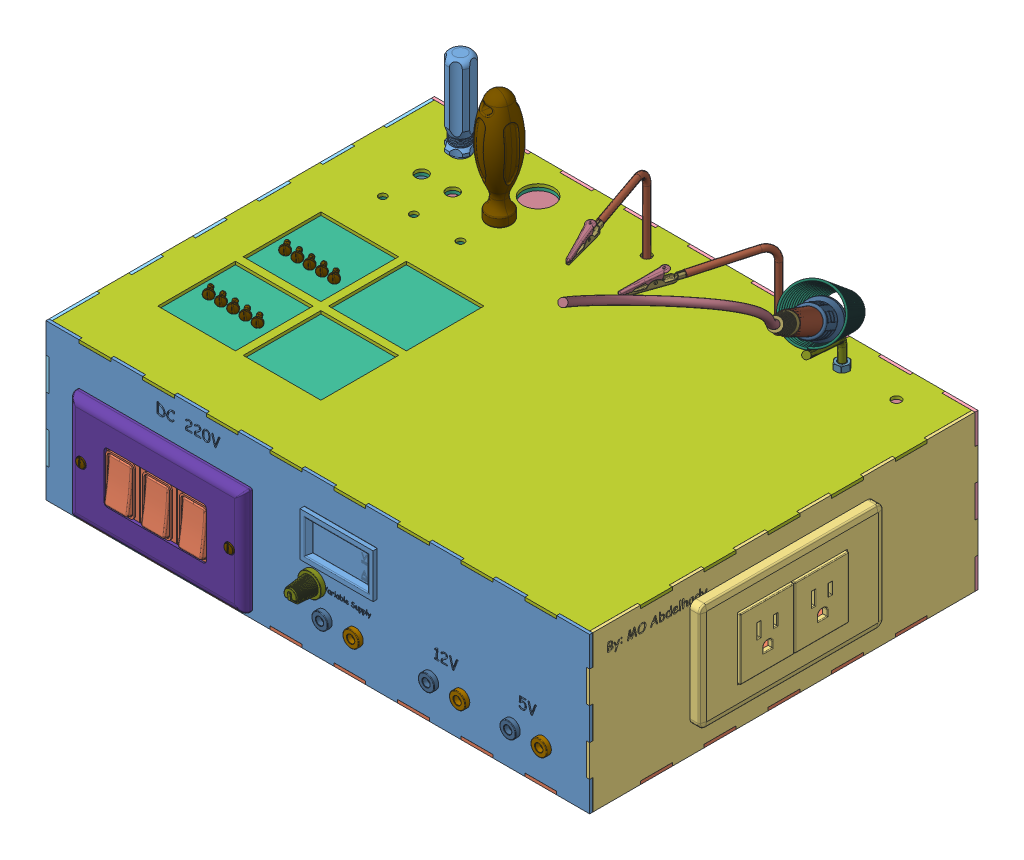
SolidWorks assembly Assem1, configuration Default. Lengths in mm.
Overall size (494.19 440.25 387.65).
70 component instances, 40 part files, 94 mates.
Components (placement in the parent):
- Part1-2: Part1 [Default] at (-4708.236 -838.5854 8887.5) size (355.6 101.6 2)
- Part5-2: Part5 [Default] at (-4427.6361 358.0877 11910.8107) x (1 0 0) z (0 1 0) size (355.6 254 2)
- Part2-1: Part2 [Default] at (116.9116 1704.849 11965.8396) x (0 -1 0) z (1 0 0) size (101.6 254 2)
- Part3-1: Part3 [Default] at (-4417.07 -837.1123 8635.4656) size (355.6 101.6 2)
- Part4-1: Part4 [Default] at (-186.7202 1702.8877 5671.7962) x (0 -1 0) z (-1 0 0) size (101.6 254 2)
- Part7-1: Part7 [Default] at (-1787.3775 455.6877 11453.9433) x (1 0 0) z (0 1 0) size (132.08 218.44 2)
- Part6-2: Part6 [Default] at (-4806.0896 457.6877 12028.9804) x (1 0 0) z (0 1 0) size (355.6 254 2)
- pot-1: pot [Default] at (-37.3978 423.1359 8904.7656) x (0 0 1) z (-1 0 0) size (29.51 24 17)
- banana_red-1: banana_red [Female, Banana Plug] at (-10.4767 405.8848 8916.4654) x (-0.682339 -0.731036 0) z (0 0 -1) size (10.54 10.54 28.12)
- banana_red-2: banana_red [Female, Banana Plug] at (59.2002 405.8848 8916.4654) x (0.821462 0.570264 0) z (0 0 -1) size (10.54 10.54 28.12)
- banana_red-3: banana_red [Female, Banana Plug] at (112.5315 405.8176 8916.4654) x (0.982462 0.186463 0) z (0 0 -1) size (10.54 10.54 28.12)
- banana_black-1: banana_black [Female, Banana Plug] at (-30.7967 405.8848 8916.4654) x (-0.579177 0.815202 0) z (0 0 -1) size (10.54 10.54 28.12)
- banana_black-2: banana_black [Female, Banana Plug] at (38.8802 405.8848 8916.4654) x (0.358694 0.933455 0) z (0 0 -1) size (10.54 10.54 28.12)
- banana_black-3: banana_black [Female, Banana Plug] at (92.2115 405.8176 8916.4654) x (-0.984112 -0.177551 0) z (0 0 -1) size (10.54 10.54 28.12)
- gang-1: gang [Default] at (-119.8752 393.7363 8922.0156)
- ss-2: ss [Default] at (-179.636 431.6464 8913.5932)
- ss-3: ss [Default] at (162.4549 435.7717 8943.6286)
- ss-4: ss [Default] at (-211.6466 368.7355 8918.2875)
- Part28-1: Part28 [Default] at (33.1958 473.157 8680.0698) x (-0.265256 0 0.964178) z (-0.964178 0 -0.265256) size (52 152 4)
- Part28-2: Part28 [Default] at (-53.1642 473.157 8680.0698) x (0.327401 0 0.944885) z (-0.944885 0 0.327401) size (52 152 4)
- Crocodile Clip.STEP-1: Crocodile Clip.STEP [Default] at (-30.6867 532.0877 8743.7186) x (0.944885 0 -0.327401) z (0.327401 0 0.944885) size (5.6 9.22 35.15)
  - Crocodile clip_01.STEP-1: Crocodile clip_01.STEP [Default] x (-1 0 0) z (0 0 -1) size (5.6 6.69 35)
  - Crocodile clip_02.STEP-1: Crocodile clip_02.STEP [Default] at (0 -0.0209 0) x (-1 0 0) z (0 0 -1) size (5.6 9.22 27.41)
- Crocodile Clip.STEP-2: Crocodile Clip.STEP [Default] at (14.9054 532.0877 8745.0457) x (0.964178 0 0.265256) z (-0.265256 0 0.964178) size (5.6 9.22 35.15)
  - Crocodile clip_01.STEP-1: Crocodile clip_01.STEP [Default] x (-1 0 0) z (0 0 -1) size (5.6 6.69 35)
  - Crocodile clip_02.STEP-1: Crocodile clip_02.STEP [Default] at (0 -0.0209 0) x (-1 0 0) z (0 0 -1) size (5.6 9.22 27.41)
- Switch KCD2 16A 220V-1: Switch KCD2 16A 220V [默认] at (102.178 430.6557 8657.4656) x (1 0 0) z (0 0 -1) size (25.5 32.5 34.2)
- plug v2.step-1: plug v2.step [Default] at (-68.1079 343.9302 8680.6226) x (0.174516 0.48804 0.855197) z (0.287949 0.805262 -0.518303) size (51.69 23.18 116.16)
  - socket.step-1: socket.step [Default] at origin size (51.69 23.18 116.16)
- Knob v3.step-1: Knob v3.step [Default] at (-37.3978 423.1359 8912.1656) x (-0.990885 -0.134707 0) z (0 0 1) size (15.25 15.25 17.66)
  - Knob_1.step-1: Knob_1.step [Default] at origin size (15.25 15.25 17.66)
- Antimicrobial Treated Plastic Wallplate, 1 Gang-1: Antimicrobial Treated Plastic Wallplate, 1 Gang [Default] at (-134.7693 421.1897 8913.4656) x (0 -1 0) z (0 0 1) size (70 114 8.01)
  - Antimicrobial Treated Plastic Wallplate, 1 Gang-1: Antimicrobial Treated Plastic Wallplate, 1 Gang [Default] at origin size (70 114 6.5)
  - Pan Head Slotted Screw, Antimicrobial Treated Plastic Wallplate, 1 Gang-1: Pan Head Slotted Screw, Antimicrobial Treated Plastic Wallplate, 1 Gang [default] at (0 48.5 3.73) size (6 6 8.01)
  - Pan Head Slotted Screw, Antimicrobial Treated Plastic Wallplate, 1 Gang-3: Pan Head Slotted Screw, Antimicrobial Treated Plastic Wallplate, 1 Gang [default] at (0 -48.5 3.73) size (6 6 8.01)
- volt_amp_dis-1: volt_amp_dis [Default] at (-19.9687 448.5599 8913.4656) size (47.8 28.8 40.1)
- MK Modular Switch.dwg-1: MK Modular Switch.dwg [Default] at (-10362.3917 377.0094 14999.0836) x (1 0 0) z (0 1 0) size (23.5 12.91 36.5)
- MK Modular Switch.dwg-2: MK Modular Switch.dwg [Default] at (-10338.2387 377.0094 14999.0836) x (1 0 0) z (0 1 0) size (23.5 12.91 36.5)
- MK Modular Switch.dwg-3: MK Modular Switch.dwg [Default] at (-10314.0917 377.0094 14999.0836) x (1 0 0) z (0 1 0) size (23.5 12.91 36.5)
- AC WALL PLUG-1: AC WALL PLUG [Predeterminado] at (142.8798 434.2477 8787.9056) x (0 1 0) z (1 0 0) size (70 120 8.5)
- Soldering_V2.step-1: Soldering_V2.step [Default] at (59.1534 499.5411 8656.9021) x (0.554079 -0.017452 0.832281) z (0.009671 0.999848 0.014528) size (372.66 84.68 286.39)
  - 2025-05-26-17-25-25-548.step-1: 2025-05-26-17-25-25-548.step [Default] at (85.6796 0 86.8505) x (-0.819152 0 -0.573576) z (0.573576 0 -0.819152) size (432.24 84.05 32.4)
    - 2025-05-26-17-25-25-545.step-1: 2025-05-26-17-25-25-545.step [Default] at (74.0317 0 27.5002) x (0 0.642788 -0.766044) z (1 0 0) size (6.5 6.5 40)
    - 2025-05-26-17-25-25-546_1.step-1: 2025-05-26-17-25-25-546_1.step [Default] at origin size (39.5 3.6 3.6)
    - 2025-05-26-17-25-25-546_2.step-1: 2025-05-26-17-25-25-546_2.step [Default] at (60.0317 0 27.5002) x (0 0.642788 -0.766044) z (1 0 0) size (12 12 40.5)
    - 2025-05-26-17-25-25-546_3.step-1: 2025-05-26-17-25-25-546_3.step [Default] at (53.6317 0 27.5002) x (0 0.642788 -0.766044) z (1 0 0) size (12.62 12 7.4)
    - 2025-05-26-17-25-25-547_2.step-1: 2025-05-26-17-25-25-547_2.step [Default] at (75.0317 0 27.5002) x (0 0.642788 -0.766044) z (1 0 0) size (10.9 10.9 24.3)
    - 2025-05-26-17-25-25-546_4.step-1: 2025-05-26-17-25-25-546_4.step [Default] at (77.4998 0 27.5002) x (0 0.642788 -0.766044) z (1 0 0) size (19.5 19.5 17.5)
    - 2025-05-26-17-25-25-548_1.step-1: 2025-05-26-17-25-25-548_1.step [Default] at (33.2317 0 27.5002) x (0 0.642788 -0.766044) z (0 0.766044 0.642788) size (23 40 23)
    - 2025-05-26-17-25-25-547_3.step-1: 2025-05-26-17-25-25-547_3.step [Default] at (-23.8135 -0.0269 27.4359) x (0 0.642788 -0.766044) z (1 0 0) size (20 20 100)
    - 2025-05-26-17-25-25-548_2.step-1: 2025-05-26-17-25-25-548_2.step [Default] at (-66.7683 0 27.5002) x (0 0.642788 -0.766044) z (1 0 0) size (12.38 12.35 33)
    - 2025-05-26-17-25-25-547_4.step-1: 2025-05-26-17-25-25-547_4.step [Default] at origin size (218.45 77.53 14.6)
  - 2025-05-26-17-25-25-547.step-1: 2025-05-26-17-25-25-547.step [Default] at (24.735 0 -15.1296) x (0.513152 -0.397354 0.760779) z (-0.829038 0 0.559193) size (8.45 9.79 9.51)
  - 2025-05-26-17-25-25-546.step-1: 2025-05-26-17-25-25-546.step [Default] at origin size (86.94 34.2 72.24)
  - 2025-05-26-17-25-25-547_1.step-1: 2025-05-26-17-25-25-547_1.step [Default] at origin size (86.39 4.51 79.92)
  - 2025-05-26-17-25-25-549.step-1: 2025-05-26-17-25-25-549.step [Default] at origin size (9.32 8.61 4.14)
- Pan Head Slotted Screw, Antimicrobial Treated Plastic Wallplate, 1 Gang-3: Pan Head Slotted Screw, Antimicrobial Treated Plastic Wallplate, 1 Gang [default] at (-175.1729 484.6877 8843.9518) x (0.066903 -0.996571 -0.048695) z (0.588474 0 0.808516) size (6 6 8.01)
- Pan Head Slotted Screw, Antimicrobial Treated Plastic Wallplate, 1 Gang-4: Pan Head Slotted Screw, Antimicrobial Treated Plastic Wallplate, 1 Gang [default] at (-167.1729 484.6877 8843.9518) x (0.066903 -0.996571 -0.048695) z (0.588474 0 0.808516) size (6 6 8.01)
- Pan Head Slotted Screw, Antimicrobial Treated Plastic Wallplate, 1 Gang-5: Pan Head Slotted Screw, Antimicrobial Treated Plastic Wallplate, 1 Gang [default] at (-159.1729 484.6877 8843.9518) x (0.066903 -0.996571 -0.048695) z (0.588474 0 0.808516) size (6 6 8.01)
- Pan Head Slotted Screw, Antimicrobial Treated Plastic Wallplate, 1 Gang-6: Pan Head Slotted Screw, Antimicrobial Treated Plastic Wallplate, 1 Gang [default] at (-151.1729 484.6877 8843.9518) x (0.066903 -0.996571 -0.048695) z (0.588474 0 0.808516) size (6 6 8.01)
- Pan Head Slotted Screw, Antimicrobial Treated Plastic Wallplate, 1 Gang-7: Pan Head Slotted Screw, Antimicrobial Treated Plastic Wallplate, 1 Gang [default] at (-143.1729 484.6877 8843.9518) x (0.066903 -0.996571 -0.048695) z (0.588474 0 0.808516) size (6 6 8.01)
- Pan Head Slotted Screw, Antimicrobial Treated Plastic Wallplate, 1 Gang-13: Pan Head Slotted Screw, Antimicrobial Treated Plastic Wallplate, 1 Gang [default] at (-175.1729 484.6877 8793.9518) x (0.066903 -0.996571 -0.048695) z (0.588474 0 0.808516) size (6 6 8.01)
- Pan Head Slotted Screw, Antimicrobial Treated Plastic Wallplate, 1 Gang-14: Pan Head Slotted Screw, Antimicrobial Treated Plastic Wallplate, 1 Gang [default] at (-167.1729 484.6877 8793.9518) x (0.066903 -0.996571 -0.048695) z (0.588474 0 0.808516) size (6 6 8.01)
- Pan Head Slotted Screw, Antimicrobial Treated Plastic Wallplate, 1 Gang-15: Pan Head Slotted Screw, Antimicrobial Treated Plastic Wallplate, 1 Gang [default] at (-159.1729 484.6877 8793.9518) x (0.066903 -0.996571 -0.048695) z (0.588474 0 0.808516) size (6 6 8.01)
- Pan Head Slotted Screw, Antimicrobial Treated Plastic Wallplate, 1 Gang-16: Pan Head Slotted Screw, Antimicrobial Treated Plastic Wallplate, 1 Gang [default] at (-151.1729 484.6877 8793.9518) x (0.066903 -0.996571 -0.048695) z (0.588474 0 0.808516) size (6 6 8.01)
- Pan Head Slotted Screw, Antimicrobial Treated Plastic Wallplate, 1 Gang-17: Pan Head Slotted Screw, Antimicrobial Treated Plastic Wallplate, 1 Gang [default] at (-143.1729 484.6877 8793.9518) x (0.066903 -0.996571 -0.048695) z (0.588474 0 0.808516) size (6 6 8.01)
- Screwdriver ++.step-1: Screwdriver ++.step [Default] at (-122.1965 483.6877 8707.5018) x (0 1 0) z (0.97343 0 0.228986) size (146 22.57 22.57)
- Screw Driver-3: Screw Driver [Default] at (-133.0655 473.0316 8723.0915) x (0 1 0) z (-0.990829 0 -0.135122) size (126 16.24 17.02)
  - Handle-1: Handle [Default] at (10.6561 35.2182 45.1033) size (56 16.24 17.02)
  - Head-1: Head [Default] at (-59.3439 35.2182 45.1033) x (1 0 0) z (0 0.028716 0.999588) size (100 4 4)
Mates (geometry in assembly coordinates):
- Parallel2: parallel anti-aligned: plane of Part1-2 through (-212.7202 483.6877 8913.4656) normal (0 1 0); plane of Part5-2 through (-210.6288 382.0877 8911.4395) normal (0 -1 0)
- Coincident5: coincident aligned: plane of Part1-2 through (-212.7202 382.0877 8913.4656) normal (0 0 1); plane of Part5-2 through (100.4618 384.0877 8913.4656) normal (0 0 1)
- Coincident7: coincident aligned: plane of Part1-2 through (-212.7202 382.0877 8913.4656) normal (0 -1 0); plane of Part5-2 through (-210.6288 382.0877 8911.4395) normal (0 -1 0)
- Coincident8: coincident aligned: plane of Part1-2 through (142.8798 382.0877 8913.4656) normal (1 0 0); plane of Part5-2 through (142.8798 384.0877 8880.1916) normal (1 0 0)
- Parallel3: parallel anti-aligned: plane of Part5-2 through (140.8478 384.0877 8911.4336) normal (1 0 0); plane of Part2-1 through (140.8798 483.6877 8913.4656) normal (-1 0 0)
- Parallel4: parallel anti-aligned: plane of Part5-2 through (-210.6288 384.0877 8911.4395) normal (0 1 0); plane of Part2-1 through (142.8798 382.0877 8913.4656) normal (0 -1 0)
- Coincident9: coincident aligned: plane of Part1-2 through (-212.7202 483.6877 8913.4656) normal (0 1 0); plane of Part2-1 through (142.8798 483.6877 8913.4656) normal (0 1 0)
- Coincident10: coincident aligned: plane of Part1-2 through (-212.7202 382.0877 8913.4656) normal (0 0 1); plane of Part2-1 through (142.8798 483.6877 8913.4656) normal (0 0 1)
- Coincident11: coincident aligned: plane of Part1-2 through (142.8798 382.0877 8913.4656) normal (1 0 0); plane of Part2-1 through (142.8798 483.6877 8913.4656) normal (1 0 0)
- Coincident12: coincident aligned: plane of Part2-1 through (142.8798 483.6877 8913.4656) normal (0 1 0); plane of Part3-1 through (37.9778 483.6877 8661.4656) normal (0 1 0)
- Coincident13: coincident aligned: plane of Part5-2 through (121.2898 384.0877 8659.4656) normal (0 0 -1); plane of Part3-1 through (-212.7202 382.0877 8659.4656) normal (0 0 -1)
- Coincident14: coincident aligned: plane of Part2-1 through (142.8798 483.6877 8913.4656) normal (1 0 0); plane of Part3-1 through (142.8798 443.3017 8661.4656) normal (1 0 0)
- Parallel5: parallel anti-aligned: plane of Part5-2 through (-210.6882 384.0877 8661.4976) normal (-1 0 0); plane of Part4-1 through (-210.7202 483.6877 8661.8789) normal (1 0 0)
- Parallel6: parallel anti-aligned: plane of Part3-1 through (-212.7202 382.0877 8659.4656) normal (0 0 -1); plane of Part4-1 through (-212.7202 443.3017 8913.4656) normal (0 0 1)
- Coincident15: coincident aligned: plane of Part3-1 through (-212.7202 483.6877 8661.4656) normal (0 1 0); plane of Part4-1 through (-212.7202 483.6877 8911.4336) normal (0 1 0)
- Coincident16: coincident aligned: plane of Part5-2 through (-212.7202 384.0877 8692.7396) normal (-1 0 0); plane of Part4-1 through (-212.7202 483.6877 8661.8789) normal (-1 0 0)
- Coincident17: coincident aligned: plane of Part3-1 through (-212.7202 382.0877 8659.4656) normal (0 0 -1); plane of Part4-1 through (-212.7202 464.1297 8659.4656) normal (0 0 -1)
- Parallel9: parallel aligned: plane of Part5-2 through (-210.6288 384.0877 8911.4395) normal (0 1 0); plane of Part6-2 through (-212.7202 483.6877 8913.4656) normal (0 1 0)
- Parallel10: parallel aligned: plane of Part4-1 through (-212.7202 483.6877 8661.8789) normal (-1 0 0); plane of Part6-2 through (-212.7202 483.6877 8880.1916) normal (-1 0 0)
- Coincident20: coincident aligned: plane of Part4-1 through (-212.7202 483.6877 8661.8789) normal (-1 0 0); plane of Part6-2 through (-212.7202 483.6877 8838.5356) normal (-1 0 0)
- Parallel12: parallel aligned: plane of Part7-1 through (-197.1266 481.6877 8879.5113) normal (0 1 0); plane of Part6-2 through (-212.7202 483.6877 8913.4656) normal (0 1 0)
- Concentric7: concentric aligned: cylinder of Part7-1 through (-122.1965 481.6877 8682.1018) axis (0 -1 0) radius 10.16; cylinder of Part6-2 through (-122.1965 483.6877 8682.1018) axis (0 -1 0) radius 10.16
- Concentric8: concentric aligned: cylinder of Part7-1 through (-172.9965 481.6877 8732.9018) axis (0 -1 0) radius 2.54; cylinder of Part6-2 through (-172.9965 483.6877 8732.9018) axis (0 -1 0) radius 2.54
- Coincident21: coincident anti-aligned: plane of Part7-1 through (-197.1266 481.6877 8879.5113) normal (0 1 0); plane of Part6-2 through (-212.7202 481.6877 8913.4656) normal (0 -1 0)
- Coincident22: coincident aligned: plane of Part1-2 through (-212.7202 382.0877 8913.4656) normal (0 0 1); plane of Part6-2 through (-170.3022 483.6877 8913.4656) normal (0 0 1)
- Concentric9: concentric anti-aligned: cylinder of Part1-2 through (-37.3978 423.1359 8913.4656) axis (0 0 -1) radius 3.6576; cylinder of pot-1 through (-37.3978 423.1359 8927.3924) axis (0 0 1) radius 3
- Parallel13: parallel anti-aligned: plane of Part1-2 through (-212.7202 404.4397 8913.4656) normal (0 1 0); plane of pot-1 through (-13.5646 417.6359 8905.2656) normal (0 -1 0)
- Tangent1: tangent aligned: plane of Part1-2 through (-212.7202 382.0877 8913.4656) normal (0 0 1); torus of pot-1
- Concentric10: concentric anti-aligned: cylinder of Part1-2 through (-10.4767 405.8848 8913.4656) axis (0 0 -1) radius 3.2512; cylinder of banana_red-1 through (-10.4767 405.8848 8916.4654) axis (0 0 1) radius 3.175
- Concentric11: concentric anti-aligned: cylinder of Part1-2 through (59.2002 405.8848 8913.4656) axis (0 0 -1) radius 3.2512; cylinder of banana_red-2 through (59.2002 405.8848 8916.4654) axis (0 0 1) radius 3.175
- Concentric12: concentric anti-aligned: cylinder of Part1-2 through (112.5315 405.8176 8913.4656) axis (0 0 -1) radius 3.2512; cylinder of banana_red-3 through (112.5315 405.8176 8916.4654) axis (0 0 1) radius 3.175
- Concentric13: concentric anti-aligned: cylinder of Part1-2 through (92.2115 405.8176 8913.4656) axis (0 0 -1) radius 3.2512; cylinder of banana_black-3 through (92.2115 405.8176 8916.4654) axis (0 0 1) radius 3.175
- Concentric14: concentric anti-aligned: cylinder of Part1-2 through (38.8802 405.8848 8913.4656) axis (0 0 -1) radius 3.2512; cylinder of banana_black-2 through (38.8802 405.8848 8916.4654) axis (0 0 1) radius 3.175
- Concentric15: concentric anti-aligned: cylinder of Part1-2 through (-30.7967 405.8848 8913.4656) axis (0 0 -1) radius 3.2512; cylinder of banana_black-1 through (-30.7967 405.8848 8916.4654) axis (0 0 1) radius 3.175
- Coincident24: coincident anti-aligned: plane of Part1-2 through (-212.7202 382.0877 8913.4656) normal (0 0 1); plane of banana_black-1 through (-26.5002 408.9373 8913.4656) normal (0 0 -1)
- Coincident25: coincident anti-aligned: plane of Part1-2 through (-212.7202 382.0877 8913.4656) normal (0 0 1); plane of banana_red-1 through (-14.3296 409.481 8913.4656) normal (0 0 -1)
- Coincident26: coincident anti-aligned: plane of Part1-2 through (-212.7202 382.0877 8913.4656) normal (0 0 1); plane of banana_black-2 through (43.7999 403.9943 8913.4656) normal (0 0 -1)
- Coincident27: coincident anti-aligned: plane of Part1-2 through (-212.7202 382.0877 8913.4656) normal (0 0 1); plane of banana_red-2 through (62.2057 401.5552 8913.4656) normal (0 0 -1)
- Coincident28: coincident anti-aligned: plane of Part1-2 through (-212.7202 382.0877 8913.4656) normal (0 0 1); plane of banana_black-3 through (91.2757 411.0043 8913.4656) normal (0 0 -1)
- Coincident29: coincident anti-aligned: plane of Part1-2 through (-212.7202 382.0877 8913.4656) normal (0 0 1); plane of banana_red-3 through (113.5143 400.6395 8913.4656) normal (0 0 -1)
- Concentric16: concentric anti-aligned: cylinder of Part6-2 through (33.1958 483.6877 8680.0698) axis (0 -1 0) radius 3.048; cylinder of Part28-1 through (33.1958 384.0877 8680.0698) axis (0 1 0) radius 2
- Coincident33: coincident anti-aligned: plane of Part5-2 through (-210.6288 384.0877 8911.4395) normal (0 1 0); plane of Part28-1 through (33.1958 384.0877 8680.0698) normal (0 -1 0)
- Coincident34: coincident anti-aligned: plane of Part5-2 through (-210.6288 384.0877 8911.4395) normal (0 1 0); plane of Part28-2 through (-53.1642 384.0877 8680.0698) normal (0 -1 0)
- Concentric17: concentric anti-aligned: cylinder of Part6-2 through (-53.1642 483.6877 8680.0698) axis (0 -1 0) radius 3.048; cylinder of Part28-2 through (-53.1642 384.0877 8680.0698) axis (0 1 0) radius 2
- Parallel15: parallel anti-aligned: plane of Part28-2 through (-36.7941 534.0877 8727.3141) normal (0.327401 0 0.944885); plane of Crocodile Clip.STEP-1/Crocodile clip_01.STEP-1 through (-39.0619 534.1927 8728.0999) normal (-0.327401 0 -0.944885)
- Coincident37: coincident anti-aligned: plane of Part28-2 through (-36.7941 534.0877 8727.3141) normal (0.327401 0 0.944885); plane of Crocodile Clip.STEP-1/Crocodile clip_01.STEP-1 through (-39.0619 534.1927 8728.0999) normal (-0.327401 0 -0.944885)
- Coincident38: coincident anti-aligned: plane of Part28-2 through (-36.7941 534.0877 8727.3141) normal (0.327401 0 0.944885); plane of Crocodile Clip.STEP-1/Crocodile clip_01.STEP-1 through (-39.0619 534.1927 8728.0999) normal (-0.327401 0 -0.944885)
- Tangent3: tangent aligned: cylinder of Part28-2 through (-49.8902 534.0877 8689.5187) axis (0.327401 0 0.944885) radius 2; plane of Crocodile Clip.STEP-1/Crocodile clip_01.STEP-1 through (-39.0619 532.0877 8728.0999) normal (0 -1 0)
- Tangent4: tangent aligned: cylinder of Part28-2 through (-49.8902 534.0877 8689.5187) axis (0.327401 0 0.944885) radius 2; plane of Crocodile Clip.STEP-1/Crocodile clip_01.STEP-1 through (-34.9044 538.0877 8726.6593) normal (0.944885 0 -0.327401)
- Parallel16: parallel anti-aligned: plane of Part28-1 through (19.933 534.0877 8728.2787) normal (-0.265256 0 0.964178); plane of Crocodile Clip.STEP-2/Crocodile clip_01.STEP-1 through (16.8476 534.1927 8727.4299) normal (0.265256 0 -0.964178)
- Coincident39: coincident anti-aligned: plane of Part28-1 through (19.933 534.0877 8728.2787) normal (-0.265256 0 0.964178); plane of Crocodile Clip.STEP-2/Crocodile clip_01.STEP-1 through (16.8476 534.1927 8727.4299) normal (0.265256 0 -0.964178)
- Tangent8: tangent aligned: cylinder of Part28-1 through (30.5432 534.0877 8689.7116) axis (-0.265256 0 0.964178) radius 2; plane of Crocodile Clip.STEP-2/Crocodile clip_01.STEP-1 through (16.8476 532.0877 8727.4299) normal (0 -1 0)
- Tangent9: tangent aligned: cylinder of Part28-1 through (30.5432 534.0877 8689.7116) axis (-0.265256 0 0.964178) radius 2; plane of Crocodile Clip.STEP-2/Crocodile clip_01.STEP-1 through (18.0046 538.0877 8727.7482) normal (-0.964178 0 -0.265256)
- Parallel17: parallel anti-aligned: plane of Part2-1 through (142.8798 483.6877 8913.4656) normal (1 0 0); plane of Switch KCD2 16A 220V-1 through (91.528 443.1557 8675.4656) normal (-1 0 0)
- Coincident40: coincident anti-aligned: plane of Part3-1 through (-212.7202 382.0877 8659.4656) normal (0 0 -1); plane of Switch KCD2 16A 220V-1 through (114.928 415.4057 8659.4656) normal (0 0 1)
- Coincident41: coincident anti-aligned: plane of Part3-1 through (91.528 418.1557 8661.4656) normal (1 0 0); plane of Switch KCD2 16A 220V-1 through (91.528 443.1557 8675.4656) normal (-1 0 0)
- Coincident42: coincident anti-aligned: plane of Part3-1 through (113.88 418.1557 8661.4656) normal (0 1 0); plane of Switch KCD2 16A 220V-1 through (112.828 418.1557 8675.4656) normal (0 -1 0)
- Concentric18: concentric anti-aligned: cylinder of Part1-2 through (-37.3978 423.1359 8913.4656) axis (0 0 -1) radius 3.6576; cylinder of Knob v3.step-1/Knob_1.step-1 through (-37.3978 423.1359 8912.1656) axis (0 0 1) radius 6.275
- Coincident43: coincident anti-aligned: plane of pot-1 through (-37.3978 423.1359 8926.9656) normal (0 0 1); plane of Knob v3.step-1/Knob_1.step-1 through (-37.3978 423.1359 8926.9656) normal (0 0 -1)
- Parallel19: parallel anti-aligned: plane of Part3-1 through (-212.7202 382.0877 8659.4656) normal (0 0 -1); plane of plug v2.step-1/socket.step-1 through (-36.8742 431.2765 8659.4656) normal (0 0 1)
- Coincident44: coincident anti-aligned: plane of Part3-1 through (-212.7202 382.0877 8659.4656) normal (0 0 -1); plane of plug v2.step-1/socket.step-1 through (-36.8742 431.2765 8659.4656) normal (0 0 1)
- Tangent10: tangent anti-aligned: plane of Part3-1 through (-33.9042 431.3637 8661.4656) normal (0 1 0); cylinder of plug v2.step-1/socket.step-1 through (-36.4854 432.3637 8659.4656) axis (0 0 1) radius 1
- Tangent11: tangent anti-aligned: plane of Part3-1 through (-37.4602 432.8877 8661.4656) normal (0.998728 -0.050431 0); cylinder of plug v2.step-1/socket.step-1 through (-36.4854 432.3637 8659.4656) axis (0 0 1) radius 1
- Parallel20: parallel anti-aligned: plane of Part4-1 through (-212.7202 483.6877 8661.8789) normal (-1 0 0); plane of Antimicrobial Treated Plastic Wallplate, 1 Gang-1/Antimicrobial Treated Plastic Wallplate, 1 Gang-1 through (-77.7693 456.1897 8919.9656) normal (1 0 0)
- Coincident45: coincident anti-aligned: plane of Part1-2 through (-212.7202 382.0877 8913.4656) normal (0 0 1); plane of Antimicrobial Treated Plastic Wallplate, 1 Gang-1/Antimicrobial Treated Plastic Wallplate, 1 Gang-1 through (-134.7693 421.1897 8913.4656) normal (0 0 -1)
- Coincident46: coincident aligned: plane of Part1-2 through (-212.7202 404.4397 8913.4656) normal (0 1 0); plane of Antimicrobial Treated Plastic Wallplate, 1 Gang-1/Antimicrobial Treated Plastic Wallplate, 1 Gang-1 through (-168.1693 404.4397 8913.4656) normal (0 1 0)
- Coincident51: coincident anti-aligned: plane of Part1-2 through (-212.7202 435.7099 8913.4656) normal (0 1 0); plane of volt_amp_dis-1 through (2.7313 435.7099 8894.2656) normal (0 -1 0)
- Coincident52: coincident anti-aligned: plane of Part1-2 through (2.7313 382.0877 8913.4656) normal (-1 0 0); plane of volt_amp_dis-1 through (2.7313 461.4099 8894.2656) normal (1 0 0)
- Coincident53: coincident anti-aligned: plane of Part1-2 through (-212.7202 382.0877 8913.4656) normal (0 0 1); plane of volt_amp_dis-1 through (-19.9687 448.5599 8913.4656) normal (0 0 -1)
- Parallel24: parallel anti-aligned: plane of Part1-2 through (-212.7202 382.0877 8913.4656) normal (0 0 1); plane of MK Modular Switch.dwg-1 through (-158.9193 420.1897 8909.9656) normal (0 0 -1)
- Coincident54: coincident anti-aligned: plane of Antimicrobial Treated Plastic Wallplate, 1 Gang-1/Antimicrobial Treated Plastic Wallplate, 1 Gang-1 through (-134.7693 421.1897 8917.9656) normal (0 0 -1); plane of MK Modular Switch.dwg-1 through (-158.9193 420.1897 8917.9656) normal (0 0 1)
- Coincident55: coincident anti-aligned: plane of Antimicrobial Treated Plastic Wallplate, 1 Gang-1/Antimicrobial Treated Plastic Wallplate, 1 Gang-1 through (-168.1693 404.4397 8913.4656) normal (1 0 0); plane of MK Modular Switch.dwg-1 through (-168.1693 420.1897 8918.4656) normal (-1 0 0)
- Coincident56: coincident anti-aligned: plane of Antimicrobial Treated Plastic Wallplate, 1 Gang-1/Antimicrobial Treated Plastic Wallplate, 1 Gang-1 through (-168.1693 404.4397 8913.4656) normal (0 1 0); plane of MK Modular Switch.dwg-1 through (-158.9193 404.4397 8918.4656) normal (0 -1 0)
- Parallel25: parallel anti-aligned: plane of Part1-2 through (-212.7202 382.0877 8913.4656) normal (0 0 1); plane of MK Modular Switch.dwg-2 through (-134.7663 420.1897 8909.9656) normal (0 0 -1)
- Coincident57: coincident aligned: plane of MK Modular Switch.dwg-1 through (-158.9193 420.1897 8917.9656) normal (0 0 1); plane of MK Modular Switch.dwg-2 through (-134.7663 420.1897 8917.9656) normal (0 0 1)
- Coincident59: coincident anti-aligned: plane of Antimicrobial Treated Plastic Wallplate, 1 Gang-1/Antimicrobial Treated Plastic Wallplate, 1 Gang-1 through (-168.1693 404.4397 8913.4656) normal (0 1 0); plane of MK Modular Switch.dwg-2 through (-134.7663 404.4397 8918.4656) normal (0 -1 0)
- Parallel26: parallel anti-aligned: plane of MK Modular Switch.dwg-2 through (-134.7663 420.1897 8917.9656) normal (0 0 1); plane of MK Modular Switch.dwg-3 through (-110.6193 420.1897 8909.9656) normal (0 0 -1)
- Coincident60: coincident aligned: plane of MK Modular Switch.dwg-2 through (-134.7663 420.1897 8917.9656) normal (0 0 1); plane of MK Modular Switch.dwg-3 through (-110.6193 420.1897 8917.9656) normal (0 0 1)
- Coincident61: coincident anti-aligned: plane of Antimicrobial Treated Plastic Wallplate, 1 Gang-1/Antimicrobial Treated Plastic Wallplate, 1 Gang-1 through (-101.3693 404.4397 8913.4656) normal (-1 0 0); plane of MK Modular Switch.dwg-3 through (-101.3693 420.1897 8918.4656) normal (1 0 0)
- Coincident62: coincident anti-aligned: plane of Antimicrobial Treated Plastic Wallplate, 1 Gang-1/Antimicrobial Treated Plastic Wallplate, 1 Gang-1 through (-168.1693 404.4397 8913.4656) normal (0 1 0); plane of MK Modular Switch.dwg-3 through (-110.6193 404.4397 8918.4656) normal (0 -1 0)
- Coincident63: coincident anti-aligned: plane of Part1-2 through (-98.8693 382.0877 8913.4656) normal (-1 0 0); plane of MK Modular Switch.dwg-3 through (-98.8693 420.1897 8907.9656) normal (1 0 0)
- Parallel29: parallel anti-aligned: plane of Part2-1 through (142.8798 483.6877 8913.4656) normal (1 0 0); plane of AC WALL PLUG-1 through (148.8798 434.2477 8787.9056) normal (-1 0 0)
- Parallel31: parallel aligned: plane of Part1-2 through (-212.7202 382.0877 8913.4656) normal (0 0 1); plane of AC WALL PLUG-1 through (149.8798 399.2477 8847.9056) normal (0 0 1)
- Coincident67: coincident anti-aligned: plane of Part2-1 through (142.8798 483.6877 8913.4656) normal (1 0 0); plane of AC WALL PLUG-1 through (142.8798 434.2477 8787.9056) normal (-1 0 0)
- Coincident68: coincident anti-aligned: plane of Part2-1 through (142.8798 455.7477 8913.4656) normal (0 -1 0); plane of AC WALL PLUG-1 through (142.8798 455.7477 8823.9056) normal (0 1 0)
- Coincident69: coincident anti-aligned: plane of Part2-1 through (142.8798 483.6877 8750.9056) normal (0 0 1); plane of AC WALL PLUG-1 through (142.8798 413.7477 8750.9056) normal (0 0 -1)
- Coincident70: coincident aligned: plane of Part2-1 through (142.8798 483.6877 8913.4656) normal (0 1 0); plane of Part6-2 through (-212.7202 483.6877 8913.4656) normal (0 1 0)
- Concentric23: concentric aligned: cylinder of Part6-2 through (74.577 483.6877 8680.0698) axis (0 -1 0) radius 3.048; cylinder of Soldering_V2.step-1/2025-05-26-17-25-25-547_1.step-1 through (74.577 484.8478 8680.0698) axis (0 -1 0) radius 2.204
- Coincident74: coincident anti-aligned: plane of Part6-2 through (-212.7202 483.6877 8913.4656) normal (0 1 0); plane of Soldering_V2.step-1/2025-05-26-17-25-25-547.step-1 through (69.9818 483.6877 8680.8176) normal (0 -1 0)
- Tangent13: tangent anti-aligned: plane of Part7-1 through (-197.1266 481.6877 8879.5113) normal (0 1 0); cylinder of Pan Head Slotted Screw, Antimicrobial Treated Plastic Wallplate, 1 Gang-3 through (-177.4679 484.6877 8840.7986) axis (-0.588474 0 -0.808516) radius 3
- Concentric27: concentric aligned: cylinder of Part6-2 through (-122.1965 483.6877 8707.5018) axis (0 -1 0) radius 4.064; cylinder of Screwdriver ++.step-1 through (-122.1965 423.6877 8707.5018) axis (0 -1 0) radius 2.5
- Coincident78: coincident anti-aligned: plane of Part6-2 through (-212.7202 483.6877 8913.4656) normal (0 1 0); plane of Screwdriver ++.step-1 through (-122.8376 483.6877 8710.2274) normal (0 -1 0)
- Concentric30: concentric aligned: cylinder of Part6-2 through (-172.9965 483.6877 8682.1018) axis (0 -1 0) radius 5.08; cylinder of Screw Driver-3/Head-1 through (-172.9965 413.6877 8682.1018) axis (0 -1 0) radius 1.5
- Coincident79: coincident anti-aligned: plane of Part6-2 through (-212.7202 483.6877 8913.4656) normal (0 1 0); plane of Screw Driver-3/Handle-1 through (-172.1858 483.6877 8676.1569) normal (0 -1 0)
